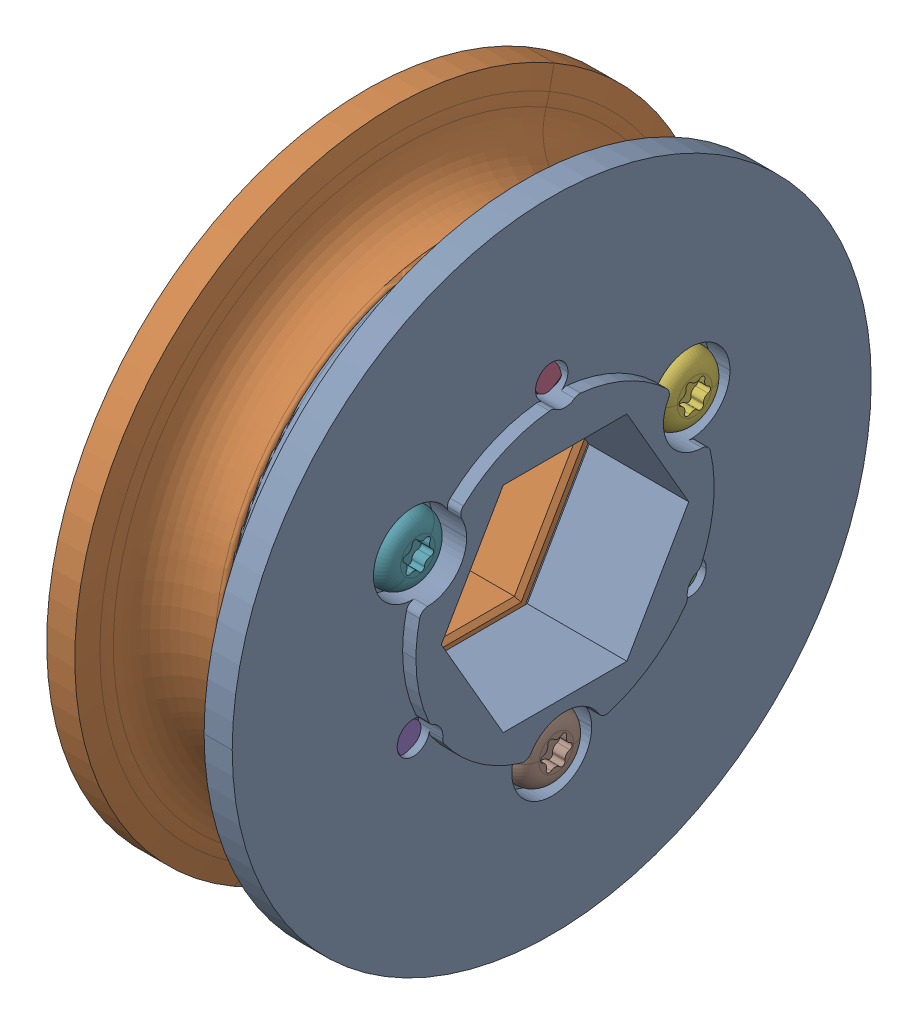
SolidWorks assembly WCP-0096 Rev6-2.step, configuration Default. Lengths in mm.
Overall size (12.65 52.05 52.05).
8 component instances, 2 part files, 0 mates.
Components (placement in the parent):
- WCP-0096-001 Rev6.step-1: WCP-0096-001 Rev6.step [Default] at origin size (7.57 38.1 38.1)
- WCP-0096-001 Rev6.step-2: WCP-0096-001 Rev6.step [Default] x (-1 0 0) z (0 0.866025 -0.5) size (7.57 38.1 38.1)
- WCP-0356 Rev1.step-1: WCP-0356 Rev1.step [Default] at (0.4817 -4.7625 -8.2489) x (0 -0.126969 0.991907) z (0 -0.991907 -0.126969) size (4.06 11.05 4.06)
- WCP-0356 Rev1.step-2: WCP-0356 Rev1.step [Default] at (0.4817 9.525 0) x (0 0.866766 0.498715) z (0 -0.498715 0.866766) size (4.06 11.05 4.06)
- WCP-0356 Rev1.step-3: WCP-0356 Rev1.step [Default] at (0.4817 -4.7625 8.2489) x (0 -0.994015 -0.109248) z (0 0.109248 -0.994015) size (4.06 11.05 4.06)
- WCP-0356 Rev1.step-4: WCP-0356 Rev1.step [Default] at (-0.4817 4.7625 -8.2489) x (0 -0.997555 0.069879) z (0 0.069879 0.997555) size (4.06 11.05 4.06)
- WCP-0356 Rev1.step-5: WCP-0356 Rev1.step [Default] at (-0.4817 4.7625 8.2489) x (0 -0.7202 -0.693767) z (0 -0.693767 0.7202) size (4.06 11.05 4.06)
- WCP-0356 Rev1.step-6: WCP-0356 Rev1.step [Default] at (-0.4817 -9.525 0) x (0 -0.997555 0.069879) z (0 0.069879 0.997555) size (4.06 11.05 4.06)
